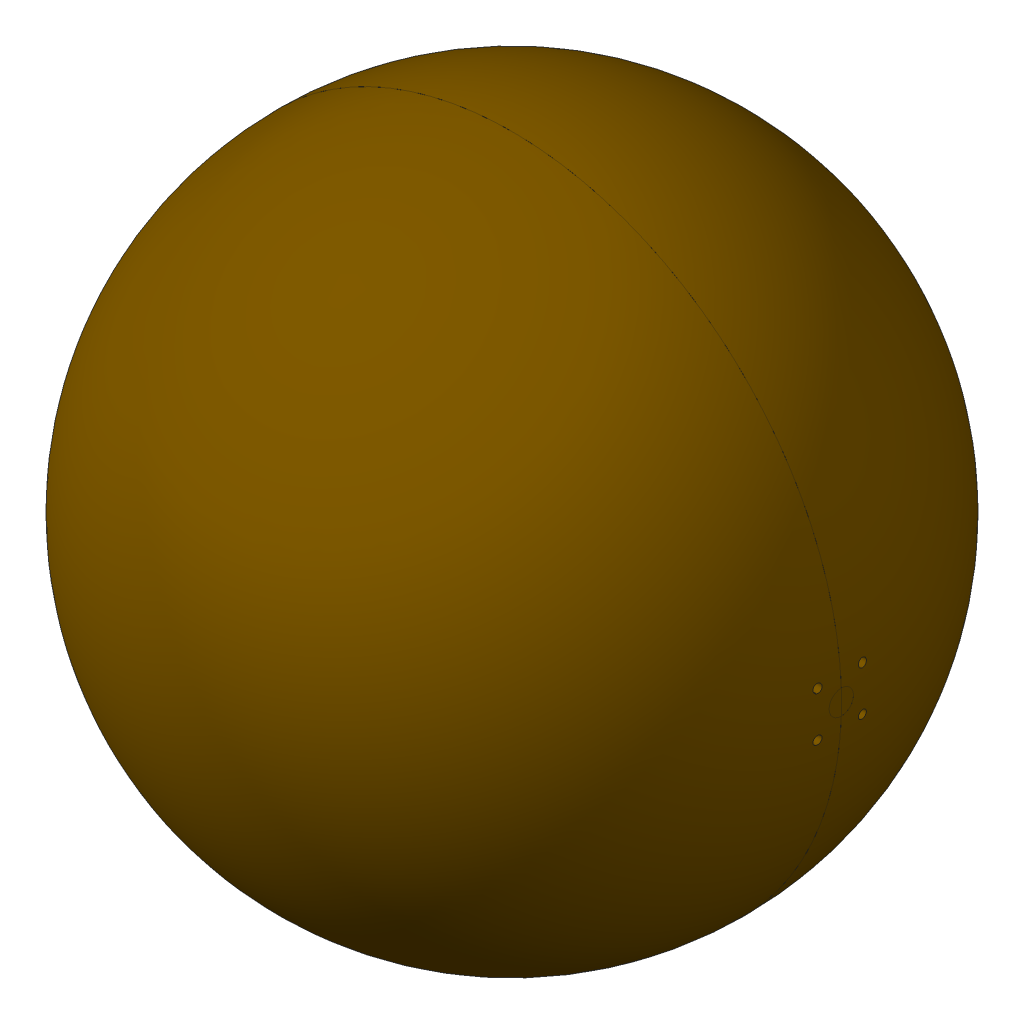
SolidWorks assembly Assembly_robot, configuration По умолчанию. Lengths in mm.
Overall size (270 270 270).
84 component instances, 36 part files, 189 mates.
Components (placement in the parent):
- Body middle part p2_1-1: Body middle part p2_1 [только доя мотора] at (-55.75 0 0) size (72.16 54.84 23.14)
- Body middle part p1-1: Body middle part p1 [только доя мотора] at (-55.6 0 0) size (19.6 42.93 42.93)
- Body middle part p3_1-1: Body middle part p3_1 [только доя мотора] at (-55.9 0 0) size (19.84 11.51 10.97)
- Body middle part p3_2-1: Body middle part p3_2 [только доя мотора] at (-55.9 0 -33.729) size (19.6 9.2 9.2)
- Body middle part p2_2-1: Body middle part p2_2 [только доя мотора] at (-55.75 0 0) size (72 54.84 18.08)
- Body right part-1: Body right part [для аккумулятора] at (114.6 0 0) x (-1 0 0) z (0 -1 0) size (59 42.93 54.93)
- Body left part-1: Body left part [для аккумулятора] at (-114.6 0 0) size (59 42.93 42.93)
- Shaft 4х280mm-1: Shaft 4х280mm [По умолчанию] at (117.5 16.8645 16.8645) x (0 1 0) z (0 0 1) size (4 235 4)
- Shaft 4х280mm-2: Shaft 4х280mm [По умолчанию] at (117.5 -16.8645 16.8645) x (0 1 0) z (0 0 1) size (4 235 4)
- Shaft 4х280mm-3: Shaft 4х280mm [По умолчанию] at (117.5 16.8645 -16.8645) x (0 1 0) z (0 0 1) size (4 235 4)
- Shaft 4х280mm-4: Shaft 4х280mm [По умолчанию] at (117.5 -16.8645 -16.8645) x (0 1 0) z (0 0 1) size (4 235 4)
- Bearing small-1: Bearing small [По умолчанию] at (112.3 0 0) x (0 1 0) z (0 0 1) size (15 5 15)
- Bearing moumt-1: Bearing moumt [под подшипник] at (112.6 0 0) x (0 0.707107 -0.707107) z (0 0.707107 0.707107) size (36.3 7.8 36.3)
- Bearing small-2: Bearing small [По умолчанию] at (-107.3 0 0) x (0 1 0) z (0 0 1) size (15 5 15)
- Bearing moumt-2: Bearing moumt [под подшипник] at (-112.6 0 0) x (0 -0.707107 -0.707107) z (0 -0.707107 0.707107) size (36.3 7.8 36.3)
- IG320014-1: IG320014 [По умолчанию] at (-68.8 0 0) size (118.3 36 36) (flexible)
  - IG320014 ч2 (мотор)-1: IG320014 ч2 (мотор) [По умолчанию] at origin size (76 36 36)
  - IG320014 ч1 (редуктор)-1: IG320014 ч1 (редуктор) [По умолчанию] at origin size (26 35 35)
  - IG320014 ч3 (вал)-1: IG320014 ч3 (вал) [По умолчанию] at (16.3 0 0) x (0 -0.305233 0.952278) z (0 -0.952278 -0.305233) size (6 16.3 6)
- Screw M3x10-1: Screw M3x10 [По умолчанию] at (-57.8 9.1924 9.1924) x (0 -1 0) z (0 0 1) size (5.7 12.2 5.7)
- Screw M3x10-2: Screw M3x10 [По умолчанию] at (-57.8 9.1924 -9.1924) x (0 -1 0) z (0 0 1) size (5.7 12.2 5.7)
- Screw M3x10-3: Screw M3x10 [По умолчанию] at (-57.8 -9.1924 -9.1924) x (0 -1 0) z (0 0 1) size (5.7 12.2 5.7)
- Screw M3x10-4: Screw M3x10 [По умолчанию] at (-57.8 -9.1924 9.1924) x (0 -1 0) z (0 0 1) size (5.7 12.2 5.7)
- Screw M3x10-5: Screw M3x10 [По умолчанию] at (-116.8 9.1924 -9.1924) x (0 -1 0) z (0 0 1) size (5.7 12.2 5.7)
- Screw M3x10-6: Screw M3x10 [По умолчанию] at (-116.8 9.1924 9.1924) x (0 -1 0) z (0 0 1) size (5.7 12.2 5.7)
- Screw M3x10-7: Screw M3x10 [По умолчанию] at (-116.8 -9.1924 -9.1924) x (0 -1 0) z (0 0 1) size (5.7 12.2 5.7)
- Screw M3x10-8: Screw M3x10 [По умолчанию] at (-116.8 -9.1924 9.1924) x (0 -1 0) z (0 0 1) size (5.7 12.2 5.7)
- Screw M3x10-9: Screw M3x10 [По умолчанию] at (116.8 9.1924 -9.1924) x (0 1 0) z (0 0 1) size (5.7 12.2 5.7)
- Screw M3x10-10: Screw M3x10 [По умолчанию] at (116.8 -9.1924 -9.1924) x (0 1 0) z (0 0 1) size (5.7 12.2 5.7)
- Screw M3x10-11: Screw M3x10 [По умолчанию] at (116.8 9.1924 9.1924) x (0 1 0) z (0 0 1) size (5.7 12.2 5.7)
- Screw M3x10-12: Screw M3x10 [По умолчанию] at (116.8 -9.1924 9.1924) x (0 1 0) z (0 0 1) size (5.7 12.2 5.7)
- Coupling-1: Coupling [По умолчанию] at (-58.8 0 0) x (0 0.305233 -0.952278) z (0 0.952278 0.305233) size (18 25 20.23)
- Shaft 6х60mm-1: Shaft 6х60mm [По умолчанию] at (-69.8 0 0) x (0 -0.305233 0.952278) z (0 -0.952278 -0.305233) size (6 60 5.3)
- Screw M3x10-14: Screw M3x10 [По умолчанию] at (-78.8 12.7891 4.0993) x (-0.440876 -0.273967 0.854734) z (0.897568 -0.13457 0.419836) size (5.7 12.2 5.7)
- Screw M3x10-15: Screw M3x10 [По умолчанию] at (-63.8 12.7891 4.0993) x (0.719714 -0.211914 0.661138) z (0.69427 0.21968 -0.685368) size (5.7 12.2 5.7)
- Servo mount v2-1: Servo mount v2 [По умолчанию] at (-13 -0.0035 -0.1355) x (0 0 -1) z (0 -1 0) size (31.72 46 59.48)
- MG995_Servo-1: MG995_Servo [Default] at (65.9061 61.1075 44.196) x (0 1 0) z (-1 0 0) size (60.1 47.6 22.25) (flexible)
  - TowerPro-MG995-1: TowerPro-MG995 [Default] at (-71.4122 -13.9185 65.9061) size (60.1 40.2 19.8)
  - TowerPro-MG995_pulley-1: TowerPro-MG995_pulley [Default] at (-61.1622 -19.0185 65.9061) x (0.189958 0 0.981792) z (0.981792 0 -0.189958) size (5.79 14.9 5.78)
  - TowerPro-MG995_arm-1: TowerPro-MG995_arm [По умолчанию] at (-61.1622 -25.0185 65.9061) x (0.996011 0 -0.089235) z (0.089235 0 0.996011) size (20.5 5.3 20.5)
- Screw M4x10-1: Screw M4x10 [По умолчанию] at (5 13.9453 54.1145) x (0.157718 0.987484 0) z (-0.987484 0.157718 0) size (8 12.2 8)
- Screw M4x10-2: Screw M4x10 [По умолчанию] at (-5 13.9453 54.1145) x (0.038416 0.999262 0) z (-0.999262 0.038416 0) size (8 12.2 8)
- Screw M4x10-3: Screw M4x10 [По умолчанию] at (5 -34.5547 54.1145) x (0.758042 -0.652206 0) z (0.652206 0.758042 0) size (8 12.2 8)
- Screw M4x10-4: Screw M4x10 [По умолчанию] at (-5 -34.5547 54.1145) x (0.226836 0.973933 0) z (-0.973933 0.226836 0) size (8 12.2 8)
- Screw M3x10-16: Screw M3x10 [По умолчанию] at (-18 7.8153 39.2145) x (1 0 0) z (0 1 0) size (5.7 12.2 5.7)
- Screw M3x10-17: Screw M3x10 [По умолчанию] at (-18 -24.0547 39.2145) x (0.735572 -0.677446 0) z (0.677446 0.735572 0) size (5.7 12.2 5.7)
- Screw M3x10-18: Screw M3x10 [По умолчанию] at (18 7.8153 39.2145) x (-0.896782 0.442473 0) z (-0.442473 -0.896782 0) size (5.7 12.2 5.7)
- Screw M3x10-19: Screw M3x10 [По умолчанию] at (18 -24.0547 39.2145) x (0.107392 -0.994217 0) z (0.994217 0.107392 0) size (5.7 12.2 5.7)
- Screw M6x12-1: Screw M6x12 [По умолчанию] at (0 -0.0524 -36.2129) x (0.808509 -0.588484 0) z (-0.588484 -0.808509 0) size (10 16 10)
- Bearing small-3: Bearing small [По умолчанию] at (0 -0.0524 -32.2129) x (-0.489561 0.871969 0) z (0.871969 0.489561 0) size (15 5 15)
- Spacer-1: Spacer [По умолчанию] at (0 -0.0524 -27.2129) x (1 0 0) z (0 -1 0) size (11.8 1.5 11.8)
- Nut M3-1: Nut M3 [По умолчанию] at (18 7.8153 20.1645) x (0.5 0.866025 0) z (0.866025 -0.5 0) size (6 2.3 5.2)
- Nut M3-2: Nut M3 [По умолчанию] at (-18 7.8153 20.1645) x (0.5 0.866025 0) z (0.866025 -0.5 0) size (6 2.3 5.2)
- Nut M3-3: Nut M3 [По умолчанию] at (18 -24.0486 18.8529) x (0.5 0.866025 0) z (0.866025 -0.5 0) size (6 2.3 5.2)
- Nut M3-4: Nut M3 [По умолчанию] at (62.45 29.2845 14.9645) x (1 0 0) z (0 -1 0) size (6 2.3 5.2)
- Nut M3-5: Nut M3 [По умолчанию] at (-18 -24.0486 18.8529) x (0.5 0.866025 0) z (0.866025 -0.5 0) size (6 2.3 5.2)
- Nut M3-6: Nut M3 [По умолчанию] at (98.95 29.2845 14.9645) x (1 0 0) z (0 -1 0) size (6 2.3 5.2)
- Nut M3-7: Nut M3 [По умолчанию] at (62.45 -7.2155 14.9645) x (1 0 0) z (0 -1 0) size (6 2.3 5.2)
- Nut M3-8: Nut M3 [По умолчанию] at (98.95 -7.2155 14.9645) x (1 0 0) z (0 -1 0) size (6 2.3 5.2)
- Nut M4-1: Nut M4 [По умолчанию] at (-114.6 16.8645 -16.8645) x (0 1 0) z (0 0 1) size (7.85 3 6.8)
- Nut M4-2: Nut M4 [По умолчанию] at (-114.6 -16.8645 -16.8645) x (0 1 0) z (0 0 1) size (7.85 3 6.8)
- Nut M4-3: Nut M4 [По умолчанию] at (-114.6 -16.8645 16.8645) x (0 1 0) z (0 0 1) size (7.85 3 6.8)
- Nut M4-4: Nut M4 [По умолчанию] at (-114.6 16.8645 16.8645) x (0 1 0) z (0 0 1) size (7.85 3 6.8)
- Nut M4-5: Nut M4 [По умолчанию] at (117.6 16.8645 -16.8645) x (0 1 0) z (0 0 1) size (7.85 3 6.8)
- Nut M4-6: Nut M4 [По умолчанию] at (117.6 16.8645 16.8645) x (0 1 0) z (0 0 1) size (7.85 3 6.8)
- Nut M4-7: Nut M4 [По умолчанию] at (117.6 -16.8645 16.8645) x (0 1 0) z (0 0 1) size (7.85 3 6.8)
- Nut M4-8: Nut M4 [По умолчанию] at (117.6 -16.8645 -16.8645) x (0 1 0) z (0 0 1) size (7.85 3 6.8)
- Body battery p1-1: Body battery p1 [По умолчанию] at (-39.5 -40.8461 0) x (0 -1 0) z (0 0 1) size (38.3 19.8 40)
- Body battery p2-1: Body battery p2 [По умолчанию] at (-39.5 -40.8461 0) x (0 -1 0) z (0 0 1) size (38.3 18 40)
- new battery (tattu 11.1V 1550mAh)-1: new battery (tattu 11.1V 1550mAh) [По умолчанию] at (-37.3 -39.8461 0) x (0 1 0) z (0 0 -1) size (43.54 93.43 27)
- Screw M3x6-1: Screw M3x6 [По умолчанию] at (-29.5 -27.6961 -20.6129) x (1 0 0) z (0 -1 0) size (5.7 8.2 5.7)
- Screw M3x6-2: Screw M3x6 [По умолчанию] at (29.5 -27.6961 -20.6129) x (1 0 0) z (0 -1 0) size (5.7 8.2 5.7)
- Screw M3x6-3: Screw M3x6 [По умолчанию] at (-29.5 -27.6961 20.6129) x (1 0 0) z (0 1 0) size (5.7 8.2 5.7)
- Screw M3x6-4: Screw M3x6 [По умолчанию] at (29.5 -27.6961 20.6129) x (1 0 0) z (0 1 0) size (5.7 8.2 5.7)
- Shaft 6х30mm-1: Shaft 6х30mm [По умолчанию] at (129.8 0 0) x (0 -0.163235 0.986587) z (0 -0.986587 -0.163235) size (6 30 5.3)
- Case mount-1: Case mount [По умолчанию] at (129.8 0 0) x (0 -0.163235 0.986587) z (0 -0.986587 -0.163235) size (35 11 31.69)
- Case mount-2: Case mount [По умолчанию] at (-129.8 0 0) x (0 0.305233 -0.952278) z (0 -0.952278 -0.305233) size (35 11 31.69)
- Sinker-1: Sinker [По умолчанию] at (-0.2619 -121.0544 20.8871) x (0 0 -1) z (0.999998 -0.002164 0) size (71 47 36)
- Sinker mount bearing-1: Sinker mount bearing [По умолчанию] at (-0.0343 -15.9045 -32.2129) x (0.999998 -0.002164 0) z (-0.002164 -0.999998 0) size (25 5 50)
- Sinker mount servo-2: Sinker mount servo [По умолчанию] at (-0.0343 -15.9069 69.2145) x (0.999998 -0.002164 0) z (-0.002164 -0.999998 0) size (25 4 50)
- Sinker mount-2: Sinker mount [По умолчанию] at (-0.0977 -45.2024 68.9871) x (0.999998 -0.002164 0) z (0.002164 0.999998 0) size (25 12.6 70)
- Sinker mount-3: Sinker mount [По умолчанию] at (-0.0977 -45.2024 -27.2129) x (-0.999998 0.002164 0) z (0.002164 0.999998 0) size (25 12.6 70)
- Case half-1: Case half [По умолчанию] at origin size (270 270 135)
- Case half-2: Case half [По умолчанию] x (-1 0 0) z (0 0 -1) size (270 270 135)
Mates (geometry in assembly coordinates):
- Совпадение1: coincident: point of ?
- Совпадение2: coincident aligned: plane of Body middle part p2_1-1 through (-55.75 0 0) normal (0 0 1); plane of assembly through (0 0 0) normal (0 0 1)
- Параллельность1: parallel aligned: plane of Body middle part p2_1-1 through (-55.75 0 0) normal (1 0 0); plane of assembly through (0 0 0) normal (1 0 0)
- Концентричный1: concentric anti-aligned: cylinder of Body middle part p2_1-1 through (68.7608 16.8645 16.8645) axis (-1 0 0) radius 2.1; cylinder of Shaft 4х280mm-1 through (-117.5 16.8645 16.8645) axis (1 0 0) radius 2
- Ширина1: width anti-aligned: plane of Body middle part p2_1-1 through (-36 -19.3785 -16.1529) normal (-1 0 0); plane of Body middle part p2_1-1 through (36 0 0) normal (1 0 0); plane of Shaft 4х280mm-1 through (117.5 16.8645 16.8645) normal (1 0 0); plane of Shaft 4х280mm-1 through (-117.5 16.8645 16.8645) normal (-1 0 0)
- Концентричный2: concentric anti-aligned: cylinder of Body middle part p2_1-1 through (68.7608 -16.8645 16.8645) axis (-1 0 0) radius 2.1; cylinder of Shaft 4х280mm-2 through (-117.5 -16.8645 16.8645) axis (1 0 0) radius 2
- Совпадение4: coincident aligned: plane of Shaft 4х280mm-1 through (-117.5 16.8645 16.8645) normal (-1 0 0); plane of Shaft 4х280mm-2 through (-117.5 -16.8645 16.8645) normal (-1 0 0)
- Концентричный3: concentric anti-aligned: cylinder of Body middle part p1-1 through (-54.1 0 0) axis (1 0 0) radius 18.25; cylinder of IG320014-1/IG320014 ч1 (редуктор)-1 through (-68.8 0 0) axis (-1 0 0) radius 17.5
- Совпадение5: coincident anti-aligned: plane of Body middle part p1-1 through (-49.5 0 0) normal (1 0 0); plane of IG320014-1/IG320014 ч1 (редуктор)-1 through (-49.5 0 0) normal (-1 0 0)
- Концентричный4: concentric aligned: cylinder of Body middle part p1-1 through (55.9 9.1924 9.1924) axis (-1 0 0) radius 1.5; cylinder of IG320014-1/IG320014 ч1 (редуктор)-1 through (-42.5 9.1924 9.1924) axis (-1 0 0) radius 1.5
- Концентричный9: concentric aligned: cylinder of Body middle part p1-1 through (55.9 9.1924 -9.1924) axis (-1 0 0) radius 1.5; cylinder of Screw M3x10-2 through (-45.6 9.1924 -9.1924) axis (-1 0 0) radius 1.4
- Концентричный10: concentric aligned: cylinder of Body middle part p1-1 through (55.9 9.1924 9.1924) axis (-1 0 0) radius 1.5; cylinder of Screw M3x10-1 through (-45.6 9.1924 9.1924) axis (-1 0 0) radius 1.4
- Концентричный11: concentric aligned: cylinder of Body middle part p1-1 through (55.9 -9.1924 -9.1924) axis (-1 0 0) radius 1.5; cylinder of Screw M3x10-3 through (-45.6 -9.1924 -9.1924) axis (-1 0 0) radius 1.4
- Концентричный12: concentric aligned: cylinder of Body middle part p1-1 through (55.9 -9.1924 9.1924) axis (-1 0 0) radius 1.5; cylinder of Screw M3x10-4 through (-45.6 -9.1924 9.1924) axis (-1 0 0) radius 1.4
- Совпадение8: coincident anti-aligned: plane of Body middle part p1-1 through (-55.6 0 0) normal (-1 0 0); plane of Screw M3x10-2 through (-55.6 9.1924 -9.1924) normal (1 0 0)
- Совпадение9: coincident anti-aligned: plane of Body middle part p1-1 through (-55.6 0 0) normal (-1 0 0); plane of Screw M3x10-1 through (-55.6 9.1924 9.1924) normal (1 0 0)
- Совпадение10: coincident anti-aligned: plane of Body middle part p1-1 through (-55.6 0 0) normal (-1 0 0); plane of Screw M3x10-3 through (-55.6 -9.1924 -9.1924) normal (1 0 0)
- Совпадение11: coincident anti-aligned: plane of Body middle part p1-1 through (-55.6 0 0) normal (-1 0 0); plane of Screw M3x10-4 through (-55.6 -9.1924 9.1924) normal (1 0 0)
- Концентричный13: concentric anti-aligned: cylinder of Body middle part p1-1 through (68.9108 16.8645 16.8645) axis (-1 0 0) radius 2.1; cylinder of Shaft 4х280mm-1 through (-117.5 16.8645 16.8645) axis (1 0 0) radius 2
- Концентричный14: concentric anti-aligned: cylinder of Body middle part p1-1 through (68.9108 -16.8645 16.8645) axis (-1 0 0) radius 2.1; cylinder of Shaft 4х280mm-2 through (-117.5 -16.8645 16.8645) axis (1 0 0) radius 2
- Совпадение12: coincident anti-aligned: plane of Body middle part p2_1-1 through (-36 -19.3785 16.1529) normal (-1 0 0); plane of Body middle part p1-1 through (-36 0 0) normal (1 0 0)
- Концентричный15: concentric anti-aligned: cylinder of Body middle part p1-1 through (68.9108 16.8645 -16.8645) axis (-1 0 0) radius 2.1; cylinder of Shaft 4х280mm-3 through (-117.5 16.8645 -16.8645) axis (1 0 0) radius 2
- Совпадение13: coincident aligned: plane of Shaft 4х280mm-1 through (-117.5 16.8645 16.8645) normal (-1 0 0); plane of Shaft 4х280mm-3 through (-117.5 16.8645 -16.8645) normal (-1 0 0)
- Концентричный16: concentric anti-aligned: cylinder of Body middle part p1-1 through (68.9108 -16.8645 -16.8645) axis (-1 0 0) radius 2.1; cylinder of Shaft 4х280mm-4 through (-117.5 -16.8645 -16.8645) axis (1 0 0) radius 2
- Совпадение14: coincident aligned: plane of Shaft 4х280mm-3 through (-117.5 16.8645 -16.8645) normal (-1 0 0); plane of Shaft 4х280mm-4 through (-117.5 -16.8645 -16.8645) normal (-1 0 0)
- Концентричный17: concentric anti-aligned: cylinder of Body middle part p2_2-1 through (68.7608 -16.8645 -16.8645) axis (-1 0 0) radius 2.1; cylinder of Shaft 4х280mm-4 through (-117.5 -16.8645 -16.8645) axis (1 0 0) radius 2
- Концентричный18: concentric anti-aligned: cylinder of Body middle part p2_2-1 through (68.7608 16.8645 -16.8645) axis (-1 0 0) radius 2.1; cylinder of Shaft 4х280mm-3 through (-117.5 16.8645 -16.8645) axis (1 0 0) radius 2
- Совпадение15: coincident anti-aligned: plane of Body middle part p1-1 through (-36 0 0) normal (1 0 0); plane of Body middle part p2_2-1 through (-36 -19.3785 -16.1529) normal (-1 0 0)
- Концентричный20: concentric anti-aligned: cylinder of Body middle part p3_2-1 through (68.6108 16.8645 -16.8645) axis (-1 0 0) radius 2.1; cylinder of Shaft 4х280mm-3 through (-117.5 16.8645 -16.8645) axis (1 0 0) radius 2
- Совпадение16: coincident anti-aligned: plane of Body middle part p3_2-1 through (36 0 -33.729) normal (-1 0 0); plane of Body middle part p2_2-1 through (36 0 0) normal (1 0 0)
- Концентричный21: concentric anti-aligned: cylinder of Body middle part p3_1-1 through (68.6108 -16.8645 16.8645) axis (-1 0 0) radius 2.1; cylinder of Shaft 4х280mm-2 through (-117.5 -16.8645 16.8645) axis (1 0 0) radius 2
- Совпадение17: coincident anti-aligned: plane of Body middle part p2_1-1 through (36 -19.3785 16.1529) normal (1 0 0); plane of Body middle part p3_1-1 through (36 0 0) normal (-1 0 0)
- Концентричный22: concentric anti-aligned: cylinder of Bearing small-2 through (-112.3 0 0) axis (1 0 0) radius 7.5; cylinder of Bearing moumt-2 through (-107.3 0 0) axis (-1 0 0) radius 7.6
- Совпадение18: coincident anti-aligned: plane of Bearing small-2 through (-107.3 0 0) normal (1 0 0); plane of Bearing moumt-2 through (-107.3 0 0) normal (-1 0 0)
- Совпадение19: coincident anti-aligned: plane of Body left part-1 through (-112.6 0 0) normal (1 0 0); plane of Bearing moumt-2 through (-112.6 0 0) normal (-1 0 0)
- Концентричный23: concentric aligned: cylinder of Body left part-1 through (-55.6 0 0) axis (-1 0 0) radius 18.25; cylinder of Bearing moumt-2 through (-107.3 0 0) axis (-1 0 0) radius 18.15
- Концентричный24: concentric anti-aligned: cylinder of Body left part-1 through (-42.5892 16.8645 16.8645) axis (-1 0 0) radius 2.1; cylinder of Shaft 4х280mm-1 through (-117.5 16.8645 16.8645) axis (1 0 0) radius 2
- Концентричный25: concentric anti-aligned: cylinder of Body left part-1 through (-42.5892 -16.8645 16.8645) axis (-1 0 0) radius 2.1; cylinder of Shaft 4х280mm-2 through (-117.5 -16.8645 16.8645) axis (1 0 0) radius 2
- Концентричный26: concentric anti-aligned: cylinder of Body left part-1 through (-55.6 9.1924 9.1924) axis (-1 0 0) radius 1.5; cylinder of Bearing moumt-2 through (-112.6 9.1924 9.1924) axis (1 0 0) radius 1.3
- Концентричный27: concentric aligned: cylinder of Body left part-1 through (-55.6 9.1924 -9.1924) axis (-1 0 0) radius 1.5; cylinder of Screw M3x10-5 through (-104.6 9.1924 -9.1924) axis (-1 0 0) radius 1.4
- Концентричный28: concentric aligned: cylinder of Body left part-1 through (-55.6 9.1924 9.1924) axis (-1 0 0) radius 1.5; cylinder of Screw M3x10-6 through (-104.6 9.1924 9.1924) axis (-1 0 0) radius 1.4
- Концентричный29: concentric aligned: cylinder of Body left part-1 through (-55.6 -9.1924 -9.1924) axis (-1 0 0) radius 1.5; cylinder of Screw M3x10-7 through (-104.6 -9.1924 -9.1924) axis (-1 0 0) radius 1.4
- Концентричный30: concentric aligned: cylinder of Body left part-1 through (-55.6 -9.1924 9.1924) axis (-1 0 0) radius 1.5; cylinder of Screw M3x10-8 through (-104.6 -9.1924 9.1924) axis (-1 0 0) radius 1.4
- Совпадение20: coincident anti-aligned: plane of Body left part-1 through (-114.6 0 0) normal (-1 0 0); plane of Screw M3x10-6 through (-114.6 9.1924 9.1924) normal (1 0 0)
- Совпадение21: coincident anti-aligned: plane of Body left part-1 through (-114.6 0 0) normal (-1 0 0); plane of Screw M3x10-5 through (-114.6 9.1924 -9.1924) normal (1 0 0)
- Совпадение22: coincident anti-aligned: plane of Body left part-1 through (-114.6 0 0) normal (-1 0 0); plane of Screw M3x10-7 through (-114.6 -9.1924 -9.1924) normal (1 0 0)
- Совпадение23: coincident anti-aligned: plane of Body left part-1 through (-114.6 0 0) normal (-1 0 0); plane of Screw M3x10-8 through (-114.6 -9.1924 9.1924) normal (1 0 0)
- Концентричный31: concentric aligned: cylinder of Bearing small-1 through (107.3 0 0) axis (1 0 0) radius 7.5; cylinder of Bearing moumt-1 through (107.3 0 0) axis (1 0 0) radius 7.6
- Совпадение24: coincident anti-aligned: plane of Bearing small-1 through (107.3 0 0) normal (-1 0 0); plane of Bearing moumt-1 through (107.3 0 0) normal (1 0 0)
- Совпадение25: coincident anti-aligned: plane of Body right part-1 through (112.6 0 0) normal (-1 0 0); plane of Bearing moumt-1 through (112.6 0 0) normal (1 0 0)
- Концентричный32: concentric aligned: cylinder of Body right part-1 through (42.5892 16.8645 16.8645) axis (1 0 0) radius 2.1; cylinder of Shaft 4х280mm-1 through (-117.5 16.8645 16.8645) axis (1 0 0) radius 2
- Концентричный33: concentric aligned: cylinder of Body right part-1 through (42.5892 -16.8645 16.8645) axis (1 0 0) radius 2.1; cylinder of Shaft 4х280mm-2 through (-117.5 -16.8645 16.8645) axis (1 0 0) radius 2
- Концентричный34: concentric aligned: cylinder of Body right part-1 through (55.6 0 0) axis (1 0 0) radius 18.25; cylinder of Bearing moumt-1 through (107.3 0 0) axis (1 0 0) radius 18.15
- Концентричный35: concentric anti-aligned: cylinder of Body right part-1 through (55.6 9.1924 -9.1924) axis (1 0 0) radius 1.5; cylinder of Bearing moumt-1 through (112.6 9.1924 -9.1924) axis (-1 0 0) radius 1.3
- Концентричный36: concentric aligned: cylinder of Body right part-1 through (55.6 9.1924 -9.1924) axis (1 0 0) radius 1.5; cylinder of Screw M3x10-9 through (104.6 9.1924 -9.1924) axis (1 0 0) radius 1.4
- Концентричный37: concentric aligned: cylinder of Body right part-1 through (55.6 -9.1924 -9.1924) axis (1 0 0) radius 1.5; cylinder of Screw M3x10-10 through (104.6 -9.1924 -9.1924) axis (1 0 0) radius 1.4
- Концентричный38: concentric aligned: cylinder of Body right part-1 through (55.6 9.1924 9.1924) axis (1 0 0) radius 1.5; cylinder of Screw M3x10-11 through (104.6 9.1924 9.1924) axis (1 0 0) radius 1.4
- Концентричный39: concentric aligned: cylinder of Body right part-1 through (55.6 -9.1924 9.1924) axis (1 0 0) radius 1.5; cylinder of Screw M3x10-12 through (104.6 -9.1924 9.1924) axis (1 0 0) radius 1.4
- Совпадение26: coincident anti-aligned: plane of Body right part-1 through (114.6 0 0) normal (1 0 0); plane of Screw M3x10-11 through (114.6 9.1924 9.1924) normal (-1 0 0)
- Совпадение27: coincident anti-aligned: plane of Body right part-1 through (114.6 0 0) normal (1 0 0); plane of Screw M3x10-10 through (114.6 -9.1924 -9.1924) normal (-1 0 0)
- Совпадение28: coincident anti-aligned: plane of Body right part-1 through (114.6 0 0) normal (1 0 0); plane of Screw M3x10-9 through (114.6 9.1924 -9.1924) normal (-1 0 0)
- Совпадение29: coincident anti-aligned: plane of Body right part-1 through (114.6 0 0) normal (1 0 0); plane of Screw M3x10-12 through (114.6 -9.1924 9.1924) normal (-1 0 0)
- Совпадение30: coincident anti-aligned: plane of Body middle part p3_1-1 through (55.6 0 0) normal (1 0 0); plane of Body right part-1 through (55.6 0 0) normal (-1 0 0)
- Концентричный40: concentric aligned: cylinder of IG320014-1/IG320014 ч3 (вал)-1 through (-68.8 0 0) axis (1 0 0) radius 3; cylinder of Coupling-1 through (-83.8 0 0) axis (1 0 0) radius 3.05
- Параллельность2: parallel anti-aligned: plane of IG320014-1/IG320014 ч3 (вал)-1 through (-56.8 2.8869 -0.8161) normal (0 0.952278 0.305233); plane of Coupling-1 through (-70.8 1.8888 3.0512) normal (0 -0.952278 -0.305233)
- Расстояние2: distance = 10 mm anti-aligned: plane of IG320014-1/IG320014 ч3 (вал)-1 through (-68.8 0 0) normal (-1 0 0); plane of Coupling-1 through (-58.8 0 0) normal (1 0 0)
- Концентричный41: concentric aligned: cylinder of Coupling-1 through (-83.8 0 0) axis (1 0 0) radius 3.05; cylinder of Shaft 6х60mm-1 through (-129.8 0 0) axis (1 0 0) radius 3
- Параллельность3: parallel anti-aligned: plane of Coupling-1 through (-70.8 1.8888 3.0512) normal (0 -0.952278 -0.305233); plane of Shaft 6х60mm-1 through (-69.8 2.9533 -1.6787) normal (0 0.952278 0.305233)
- Расстояние3: distance = 14 mm anti-aligned: plane of Coupling-1 through (-83.8 0 0) normal (-1 0 0); plane of Shaft 6х60mm-1 through (-69.8 0 0) normal (1 0 0)
- Концентричный42: concentric aligned: cylinder of Coupling-1 through (-63.8 -0.7333 -0.235) axis (0 0.952278 0.305233) radius 1.5; cylinder of Screw M3x10-15 through (-63.8 1.1713 0.3754) axis (0 0.952278 0.305233) radius 1.4
- Концентричный43: concentric aligned: cylinder of Coupling-1 through (-78.8 -0.7333 -0.235) axis (0 0.952278 0.305233) radius 1.5; cylinder of Screw M3x10-14 through (-78.8 1.1713 0.3754) axis (0 0.952278 0.305233) radius 1.4
- Совпадение36: coincident anti-aligned: plane of Coupling-1 through (-58.8 10.6941 3.4278) normal (0 0.952278 0.305233); plane of Screw M3x10-15 through (-63.8 10.6941 3.4278) normal (0 -0.952278 -0.305233)
- Совпадение37: coincident anti-aligned: plane of Coupling-1 through (-58.8 10.6941 3.4278) normal (0 0.952278 0.305233); plane of Screw M3x10-14 through (-78.8 10.6941 3.4278) normal (0 -0.952278 -0.305233)
- Совпадение38: coincident anti-aligned: plane of Body middle part p1-1 through (-55.6 0 0) normal (-1 0 0); plane of Body left part-1 through (-55.6 0 0) normal (1 0 0)
- Совпадение40: coincident anti-aligned: plane of Body middle part p2_1-1 through (-55.75 0 31.4645) normal (0 0 1); plane of Servo mount v2-1 through (-13 -0.0035 31.4645) normal (0 0 -1)
- Концентричный44: concentric aligned: cylinder of Body middle part p2_1-1 through (-18 7.8153 11.4645) axis (0 0 1) radius 1.5; cylinder of Servo mount v2-1 through (-18 7.8153 17.5443) axis (0 0 1) radius 1.5
- Параллельность4: parallel aligned: cylinder of Body middle part p2_1-1 through (-18 -24.0486 11.4645) axis (0 0 1) radius 1.5; cylinder of Servo mount v2-1 through (-18 -24.0547 17.5443) axis (0 0 1) radius 1.5
- Совпадение41: coincident anti-aligned: plane of Servo mount v2-1 through (11 -38.0447 49.4145) normal (0 0 1); plane of MG995_Servo-1/TowerPro-MG995-1 through (0 -10.3047 49.4145) normal (0 0 -1)
- Ширина2: width anti-aligned: plane of Servo mount v2-1 through (10.15 10.2953 17.6953) normal (-1 0 0); plane of Servo mount v2-1 through (-10.15 10.2953 17.6953) normal (1 0 0); plane of MG995_Servo-1/TowerPro-MG995-1 through (9.9 9.9453 21.6145) normal (1 0 0); plane of MG995_Servo-1/TowerPro-MG995-1 through (-9.9 9.9453 21.6145) normal (-1 0 0)
- Ширина3: width anti-aligned: plane of Servo mount v2-1 through (10.15 -30.9047 17.6953) normal (0 1 0); plane of Servo mount v2-1 through (10.15 10.2953 17.6953) normal (0 -1 0); plane of MG995_Servo-1/TowerPro-MG995-1 through (-9.9 -30.5547 21.6145) normal (0 -1 0); plane of MG995_Servo-1/TowerPro-MG995-1 through (-9.9 9.9453 21.6145) normal (0 1 0)
- Совпадение42: coincident aligned: plane of Body middle part p2_1-1 through (-23 -19.0486 2.0108) normal (-1 0 0); plane of Servo mount v2-1 through (-23 -19.0547 31.4645) normal (-1 0 0)
- Концентричный48: concentric aligned: cylinder of Servo mount v2-1 through (5 13.9453 37.0145) axis (0 0 1) radius 1.85; cylinder of Screw M4x10-1 through (5 13.9453 41.9145) axis (0 0 1) radius 1.85
- Концентричный49: concentric aligned: cylinder of Servo mount v2-1 through (-5 13.9453 37.0145) axis (0 0 1) radius 1.85; cylinder of Screw M4x10-2 through (-5 13.9453 41.9145) axis (0 0 1) radius 1.85
- Концентричный50: concentric aligned: cylinder of Servo mount v2-1 through (5 -34.5547 37.0145) axis (0 0 1) radius 1.85; cylinder of Screw M4x10-3 through (5 -34.5547 41.9145) axis (0 0 1) radius 1.85
- Концентричный51: concentric aligned: cylinder of Servo mount v2-1 through (-5 -34.5547 37.0145) axis (0 0 1) radius 1.85; cylinder of Screw M4x10-4 through (-5 -34.5547 41.9145) axis (0 0 1) radius 1.85
- Совпадение43: coincident anti-aligned: plane of MG995_Servo-1/TowerPro-MG995-1 through (0 -10.3047 51.9145) normal (0 0 1); plane of Screw M4x10-1 through (5 13.9453 51.9145) normal (0 0 -1)
- Совпадение44: coincident anti-aligned: plane of MG995_Servo-1/TowerPro-MG995-1 through (0 -10.3047 51.9145) normal (0 0 1); plane of Screw M4x10-2 through (-5 13.9453 51.9145) normal (0 0 -1)
- Совпадение45: coincident anti-aligned: plane of MG995_Servo-1/TowerPro-MG995-1 through (0 -10.3047 51.9145) normal (0 0 1); plane of Screw M4x10-3 through (5 -34.5547 51.9145) normal (0 0 -1)
- Совпадение46: coincident anti-aligned: plane of MG995_Servo-1/TowerPro-MG995-1 through (0 -10.3047 51.9145) normal (0 0 1); plane of Screw M4x10-4 through (-5 -34.5547 51.9145) normal (0 0 -1)
- Концентричный52: concentric aligned: cylinder of Servo mount v2-1 through (-18 7.8153 17.5443) axis (0 0 1) radius 1.5; cylinder of Screw M3x10-16 through (-18 7.8153 27.0145) axis (0 0 1) radius 1.4
- Концентричный53: concentric aligned: cylinder of Servo mount v2-1 through (-18 -24.0547 17.5443) axis (0 0 1) radius 1.5; cylinder of Screw M3x10-17 through (-18 -24.0547 27.0145) axis (0 0 1) radius 1.4
- Концентричный54: concentric aligned: cylinder of Servo mount v2-1 through (18 7.8153 17.5443) axis (0 0 1) radius 1.5; cylinder of Screw M3x10-18 through (18 7.8153 27.0145) axis (0 0 1) radius 1.4
- Концентричный55: concentric aligned: cylinder of Servo mount v2-1 through (18 -24.0547 17.5443) axis (0 0 1) radius 1.5; cylinder of Screw M3x10-19 through (18 -24.0547 27.0145) axis (0 0 1) radius 1.4
- Совпадение48: coincident anti-aligned: plane of Servo mount v2-1 through (-13 -0.0035 37.0145) normal (0 0 1); plane of Screw M3x10-18 through (18 7.8153 37.0145) normal (0 0 -1)
- Совпадение49: coincident anti-aligned: plane of Servo mount v2-1 through (-13 -0.0035 37.0145) normal (0 0 1); plane of Screw M3x10-19 through (18 -24.0547 37.0145) normal (0 0 -1)
- Совпадение50: coincident anti-aligned: plane of Servo mount v2-1 through (-13 -0.0035 37.0145) normal (0 0 1); plane of Screw M3x10-17 through (-18 -24.0547 37.0145) normal (0 0 -1)
- Совпадение51: coincident anti-aligned: plane of Servo mount v2-1 through (-13 -0.0035 37.0145) normal (0 0 1); plane of Screw M3x10-16 through (-18 7.8153 37.0145) normal (0 0 -1)
- Концентричный58: concentric aligned: cylinder of Body middle part p2_2-1 through (0 -0.0524 -1.4129) axis (0 0 -1) radius 2.5; cylinder of Spacer-1 through (0 -0.0524 -25.7129) axis (0 0 -1) radius 3.15
- Совпадение53: coincident anti-aligned: plane of Body middle part p2_2-1 through (0 -0.0524 -25.7129) normal (0 0 -1); plane of Spacer-1 through (0 -0.0524 -25.7129) normal (0 0 1)
- Концентричный59: concentric aligned: cylinder of Bearing small-3 through (0 -0.0524 -27.2129) axis (0 0 -1) radius 3; cylinder of Spacer-1 through (0 -0.0524 -25.7129) axis (0 0 -1) radius 3.15
- Совпадение54: coincident anti-aligned: plane of Bearing small-3 through (0 -0.0524 -27.2129) normal (0 0 1); plane of Spacer-1 through (0 -0.0524 -27.2129) normal (0 0 -1)
- Концентричный60: concentric aligned: cylinder of Body middle part p2_2-1 through (0 -0.0524 -1.4129) axis (0 0 -1) radius 2.5; cylinder of Screw M6x12-1 through (0 -0.0524 -20.2129) axis (0 0 -1) radius 3
- Совпадение55: coincident anti-aligned: plane of Screw M6x12-1 through (0 -0.0524 -32.2129) normal (0 0 1); plane of Bearing small-3 through (0 -0.0524 -32.2129) normal (0 0 -1)
- Концентричный61: concentric anti-aligned: cylinder of Body middle part p2_1-1 through (18 7.8153 11.4645) axis (0 0 1) radius 1.5; cylinder of Nut M3-1 through (18 7.8153 22.4645) axis (0 0 -1) radius 1.35
- Параллельность5: parallel anti-aligned: plane of Body middle part p2_1-1 through (19.525 10.4567 22.4645) normal (0 -1 0); plane of Nut M3-1 through (19.5 10.4134 22.4645) normal (0 1 0)
- Совпадение57: coincident anti-aligned: plane of Body middle part p2_1-1 through (-55.75 0 22.4645) normal (0 0 -1); plane of Nut M3-1 through (18 7.8153 22.4645) normal (0 0 1)
- Концентричный62: concentric anti-aligned: cylinder of Body middle part p2_1-1 through (18 -24.0486 11.4645) axis (0 0 1) radius 1.5; cylinder of Nut M3-3 through (18 -24.0486 21.1529) axis (0 0 -1) radius 1.35
- Параллельность6: parallel anti-aligned: plane of Body middle part p2_1-1 through (16.475 -21.4072 21.1529) normal (0 -1 0); plane of Nut M3-3 through (19.5 -21.4505 21.1529) normal (0 1 0)
- Совпадение59: coincident anti-aligned: plane of Body middle part p2_1-1 through (-55.75 0 21.1529) normal (0 0 -1); plane of Nut M3-3 through (18 -24.0486 21.1529) normal (0 0 1)
- Концентричный63: concentric anti-aligned: cylinder of Body middle part p2_1-1 through (-18 7.8153 11.4645) axis (0 0 1) radius 1.5; cylinder of Nut M3-2 through (-18 7.8153 22.4645) axis (0 0 -1) radius 1.35
- Параллельность7: parallel anti-aligned: plane of Body middle part p2_1-1 through (-16.475 10.4567 22.4645) normal (0 -1 0); plane of Nut M3-2 through (-16.5 10.4134 22.4645) normal (0 1 0)
- Совпадение61: coincident anti-aligned: plane of Body middle part p2_1-1 through (-55.75 0 22.4645) normal (0 0 -1); plane of Nut M3-2 through (-18 7.8153 22.4645) normal (0 0 1)
- Концентричный64: concentric anti-aligned: cylinder of Body middle part p2_1-1 through (-18 -24.0486 11.4645) axis (0 0 1) radius 1.5; cylinder of Nut M3-5 through (-18 -24.0486 21.1529) axis (0 0 -1) radius 1.35
- Параллельность8: parallel anti-aligned: plane of Body middle part p2_1-1 through (-19.525 -21.4072 21.1529) normal (0 -1 0); plane of Nut M3-5 through (-16.5 -21.4505 21.1529) normal (0 1 0)
- Совпадение63: coincident anti-aligned: plane of Body middle part p2_1-1 through (-55.75 0 21.1529) normal (0 0 -1); plane of Nut M3-5 through (-18 -24.0486 21.1529) normal (0 0 1)
- Концентричный65: concentric anti-aligned: cylinder of Body right part-1 through (62.45 29.2845 -21.4655) axis (0 0 1) radius 1.5; cylinder of Nut M3-4 through (62.45 29.2845 17.2645) axis (0 0 -1) radius 1.35
- Концентричный66: concentric anti-aligned: cylinder of Body right part-1 through (98.95 29.2845 -21.4655) axis (0 0 1) radius 1.5; cylinder of Nut M3-6 through (98.95 29.2845 17.2645) axis (0 0 -1) radius 1.35
- Концентричный67: concentric aligned: cylinder of Body right part-1 through (62.45 -7.2155 21.4655) axis (0 0 -1) radius 1.5; cylinder of Nut M3-7 through (62.45 -7.2155 17.2645) axis (0 0 -1) radius 1.35
- Концентричный68: concentric aligned: cylinder of Body right part-1 through (98.95 -7.2155 21.4655) axis (0 0 -1) radius 1.5; cylinder of Nut M3-8 through (98.95 -7.2155 17.2645) axis (0 0 -1) radius 1.35
- Параллельность9: parallel anti-aligned: plane of Body right part-1 through (100.475 31.9259 14.9645) normal (0 -1 0); plane of Nut M3-6 through (100.45 31.8826 17.2645) normal (0 1 0)
- Параллельность10: parallel anti-aligned: plane of Body right part-1 through (63.975 31.9259 14.9645) normal (0 -1 0); plane of Nut M3-4 through (63.95 31.8826 17.2645) normal (0 1 0)
- Параллельность11: parallel anti-aligned: plane of Body right part-1 through (63.975 -4.5741 14.9645) normal (0 -1 0); plane of Nut M3-7 through (63.95 -4.6174 17.2645) normal (0 1 0)
- Параллельность12: parallel anti-aligned: plane of Body right part-1 through (100.475 -4.5741 14.9645) normal (0 -1 0); plane of Nut M3-8 through (100.45 -4.6174 17.2645) normal (0 1 0)
- Совпадение68: coincident anti-aligned: plane of Body right part-1 through (114.6 0 14.9645) normal (0 0 1); plane of Nut M3-8 through (98.95 -7.2155 14.9645) normal (0 0 -1)
- Совпадение69: coincident anti-aligned: plane of Body right part-1 through (114.6 0 14.9645) normal (0 0 1); plane of Nut M3-7 through (62.45 -7.2155 14.9645) normal (0 0 -1)
- Совпадение70: coincident anti-aligned: plane of Body right part-1 through (114.6 0 14.9645) normal (0 0 1); plane of Nut M3-6 through (98.95 29.2845 14.9645) normal (0 0 -1)
- Совпадение71: coincident anti-aligned: plane of Body right part-1 through (114.6 0 14.9645) normal (0 0 1); plane of Nut M3-4 through (62.45 29.2845 14.9645) normal (0 0 -1)
- Концентричный73: concentric aligned: cylinder of Shaft 4х280mm-3 through (-117.5 16.8645 -16.8645) axis (1 0 0) radius 2; cylinder of Nut M4-1 through (-117.6 16.8645 -16.8645) axis (1 0 0) radius 1.85
- Концентричный74: concentric aligned: cylinder of Shaft 4х280mm-1 through (-117.5 16.8645 16.8645) axis (1 0 0) radius 2; cylinder of Nut M4-4 through (-117.6 16.8645 16.8645) axis (1 0 0) radius 1.85
- Концентричный75: concentric aligned: cylinder of Shaft 4х280mm-4 through (-117.5 -16.8645 -16.8645) axis (1 0 0) radius 2; cylinder of Nut M4-2 through (-117.6 -16.8645 -16.8645) axis (1 0 0) radius 1.85
- Концентричный76: concentric aligned: cylinder of Shaft 4х280mm-2 through (-117.5 -16.8645 16.8645) axis (1 0 0) radius 2; cylinder of Nut M4-3 through (-117.6 -16.8645 16.8645) axis (1 0 0) radius 1.85
- Совпадение76: coincident anti-aligned: plane of Body left part-1 through (-114.6 0 0) normal (-1 0 0); plane of Nut M4-3 through (-114.6 -16.8645 16.8645) normal (1 0 0)
- Совпадение77: coincident anti-aligned: plane of Body left part-1 through (-114.6 0 0) normal (-1 0 0); plane of Nut M4-2 through (-114.6 -16.8645 -16.8645) normal (1 0 0)
- Совпадение78: coincident anti-aligned: plane of Body left part-1 through (-114.6 0 0) normal (-1 0 0); plane of Nut M4-1 through (-114.6 16.8645 -16.8645) normal (1 0 0)
- Совпадение79: coincident anti-aligned: plane of Body left part-1 through (-114.6 0 0) normal (-1 0 0); plane of Nut M4-4 through (-114.6 16.8645 16.8645) normal (1 0 0)
- Концентричный77: concentric aligned: cylinder of Shaft 4х280mm-3 through (-117.5 16.8645 -16.8645) axis (1 0 0) radius 2; cylinder of Nut M4-5 through (114.6 16.8645 -16.8645) axis (1 0 0) radius 1.85
- Концентричный78: concentric aligned: cylinder of Shaft 4х280mm-1 through (-117.5 16.8645 16.8645) axis (1 0 0) radius 2; cylinder of Nut M4-6 through (114.6 16.8645 16.8645) axis (1 0 0) radius 1.85
- Концентричный79: concentric aligned: cylinder of Shaft 4х280mm-4 through (-117.5 -16.8645 -16.8645) axis (1 0 0) radius 2; cylinder of Nut M4-8 through (114.6 -16.8645 -16.8645) axis (1 0 0) radius 1.85
- Концентричный80: concentric aligned: cylinder of Shaft 4х280mm-2 through (-117.5 -16.8645 16.8645) axis (1 0 0) radius 2; cylinder of Nut M4-7 through (114.6 -16.8645 16.8645) axis (1 0 0) radius 1.85
- Совпадение80: coincident anti-aligned: plane of Body right part-1 through (114.6 0 0) normal (1 0 0); plane of Nut M4-5 through (114.6 16.8645 -16.8645) normal (-1 0 0)
- Совпадение81: coincident anti-aligned: plane of Body right part-1 through (114.6 0 0) normal (1 0 0); plane of Nut M4-6 through (114.6 16.8645 16.8645) normal (-1 0 0)
- Совпадение82: coincident anti-aligned: plane of Body right part-1 through (114.6 0 0) normal (1 0 0); plane of Nut M4-7 through (114.6 -16.8645 16.8645) normal (-1 0 0)
- Совпадение83: coincident anti-aligned: plane of Body right part-1 through (114.6 0 0) normal (1 0 0); plane of Nut M4-8 through (114.6 -16.8645 -16.8645) normal (-1 0 0)
- Ширина4: width anti-aligned: plane of Body battery p1-1 through (-37.5 -21.6961 16) normal (0 0 1); plane of Body battery p1-1 through (-37.5 -21.6961 -16) normal (0 0 -1); plane of Body battery p2-1 through (-37.5 -21.6961 -16) normal (0 0 -1); plane of Body battery p2-1 through (-37.5 -21.6961 16) normal (0 0 1)
- Ширина5: width aligned: plane of Body battery p1-1 through (-37.5 -21.6961 16) normal (0 0 1); plane of Body battery p1-1 through (-37.5 -21.6961 -16) normal (0 0 -1); plane of Body middle part p2_1-1 through (-55.75 0 16.1529) normal (0 0 -1); plane of Body middle part p2_2-1 through (-55.75 0 -16.1529) normal (0 0 1)
- Концентричный89: concentric aligned: cylinder of Body middle part p2_1-1 through (-29.5 -27.6961 -21.4645) axis (0 0 1) radius 1.35; cylinder of Body battery p1-1 through (-29.5 -27.6961 -16) axis (0 0 1) radius 1.35
- Концентричный90: concentric aligned: cylinder of Body middle part p2_1-1 through (29.5 -27.6961 -21.4645) axis (0 0 1) radius 1.35; cylinder of Body battery p2-1 through (29.5 -27.6961 -16) axis (0 0 1) radius 1.35
- Параллельность17: parallel anti-aligned: plane of Body battery p1-1 through (-39.5 -40.8461 0) normal (-1 0 0); plane of Body battery p2-1 through (37.5 -40.8461 0) normal (1 0 0)
- Параллельность18: parallel aligned: plane of Servo mount v2-1 through (-13 -40.0447 -0.1355) normal (0 -1 0); plane of Body battery p1-1 through (-37.5 -59.9961 -16) normal (0 -1 0)
- Параллельность19: parallel aligned: plane of Servo mount v2-1 through (-13 -40.0447 -0.1355) normal (0 -1 0); plane of Body battery p2-1 through (-37.5 -59.9961 -16) normal (0 -1 0)
- Ширина6: width anti-aligned: plane of new battery (tattu 11.1V 1550mAh)-1 through (36.7 -57.8461 13.5) normal (0 0 1); plane of new battery (tattu 11.1V 1550mAh)-1 through (36.7 -57.8461 -13.5) normal (0 0 -1); plane of Body battery p1-1 through (37.5 -21.6961 14) normal (0 0 -1); plane of Body battery p1-1 through (37.5 -57.9961 -14) normal (0 0 1)
- Расстояние4: distance = 0.2 mm anti-aligned: plane of new battery (tattu 11.1V 1550mAh)-1 through (-37.3 -39.8461 0) normal (-1 0 0); plane of Body battery p1-1 through (-37.5 -40.8461 0) normal (1 0 0)
- Расстояние5: distance = 0.15 mm anti-aligned: plane of Body battery p2-1 through (37.5 -57.9961 14) normal (0 1 0); plane of new battery (tattu 11.1V 1550mAh)-1 through (36.7 -57.8461 13.5) normal (0 -1 0)
- Концентричный91: concentric aligned: cylinder of Body middle part p2_2-1 through (29.5 -27.6961 21.4645) axis (0 0 -1) radius 1.35; cylinder of Screw M3x6-2 through (29.5 -27.6961 -12.4129) axis (0 0 -1) radius 1.4
- Концентричный92: concentric aligned: cylinder of Body middle part p2_2-1 through (-29.5 -27.6961 21.4645) axis (0 0 -1) radius 1.35; cylinder of Screw M3x6-1 through (-29.5 -27.6961 -12.4129) axis (0 0 -1) radius 1.4
- Совпадение92: coincident anti-aligned: plane of Body middle part p2_2-1 through (-55.75 0 -18.4129) normal (0 0 -1); plane of Screw M3x6-1 through (-29.5 -27.6961 -18.4129) normal (0 0 1)
- Совпадение93: coincident anti-aligned: plane of Body middle part p2_2-1 through (-55.75 0 -18.4129) normal (0 0 -1); plane of Screw M3x6-2 through (29.5 -27.6961 -18.4129) normal (0 0 1)
- Концентричный93: concentric aligned: cylinder of Body middle part p2_1-1 through (-29.5 -27.6961 -21.4645) axis (0 0 1) radius 1.35; cylinder of Screw M3x6-3 through (-29.5 -27.6961 12.4129) axis (0 0 1) radius 1.4
- Концентричный94: concentric aligned: cylinder of Body middle part p2_1-1 through (29.5 -27.6961 -21.4645) axis (0 0 1) radius 1.35; cylinder of Screw M3x6-4 through (29.5 -27.6961 12.4129) axis (0 0 1) radius 1.4
- Совпадение94: coincident anti-aligned: plane of Body middle part p2_1-1 through (-55.75 0 18.4129) normal (0 0 1); plane of Screw M3x6-4 through (29.5 -27.6961 18.4129) normal (0 0 -1)
- Совпадение95: coincident anti-aligned: plane of Body middle part p2_1-1 through (-55.75 0 18.4129) normal (0 0 1); plane of Screw M3x6-3 through (-29.5 -27.6961 18.4129) normal (0 0 -1)
- Концентричный95: concentric aligned: cylinder of Shaft 6х60mm-1 through (-129.8 0 0) axis (1 0 0) radius 3; cylinder of Case mount-2 through (-129.8 0 0) axis (1 0 0) radius 3.1
- Параллельность20: parallel anti-aligned: plane of Shaft 6х60mm-1 through (-69.8 2.9533 -1.6787) normal (0 0.952278 0.305233); plane of Case mount-2 through (-129.8 1.9323 2.4241) normal (0 -0.952278 -0.305233)
- Совпадение97: coincident aligned: plane of Shaft 6х60mm-1 through (-129.8 0 0) normal (-1 0 0); plane of Case mount-2 through (-129.8 0 0) normal (-1 0 0)
- Концентричный96: concentric anti-aligned: cylinder of Shaft 6х30mm-1 through (99.8 0 0) axis (1 0 0) radius 3; cylinder of Case mount-1 through (129.8 0 0) axis (-1 0 0) radius 3.1
- Параллельность21: parallel anti-aligned: plane of Shaft 6х30mm-1 through (129.8 2.6772 -2.091) normal (0 0.986587 0.163235); plane of Case mount-1 through (129.8 2.8259 -1.2744) normal (0 -0.986587 -0.163235)
- Совпадение99: coincident aligned: plane of Shaft 6х30mm-1 through (129.8 0 0) normal (1 0 0); plane of Case mount-1 through (129.8 0 0) normal (1 0 0)
- Концентричный97: concentric aligned: cylinder of Bearing small-1 through (107.3 0 0) axis (1 0 0) radius 3; cylinder of Shaft 6х30mm-1 through (99.8 0 0) axis (1 0 0) radius 3
- Расстояние6: distance = 11.7 mm anti-aligned: plane of Case mount-1 through (126.3 -5.2848 3.7843) normal (-1 0 0); plane of Body right part-1 through (114.6 0 0) normal (1 0 0)
- Концентричный98: concentric aligned: cylinder of Bearing small-3 through (0 -0.0524 -27.2129) axis (0 0 -1) radius 7.5; cylinder of Sinker mount bearing-1 through (0 -0.0524 -27.2129) axis (0 0 -1) radius 7.65
- Совпадение100: coincident aligned: plane of Bearing small-3 through (0 -0.0524 -27.2129) normal (0 0 1); plane of Sinker mount bearing-1 through (0 -0.0524 -27.2129) normal (0 0 1)
- Совпадение101: coincident anti-aligned: plane of MG995_Servo-1/TowerPro-MG995_arm-1 through (0 -0.0547 69.2145) normal (0 0 1); plane of Sinker mount servo-2 through (0 -0.0547 69.2145) normal (0 0 -1)
- Концентричный99: concentric aligned: cylinder of MG995_Servo-1/TowerPro-MG995_arm-1 through (0 -0.0547 69.2145) axis (0 0 -1) radius 1.5; cylinder of Sinker mount servo-2 through (0 -0.0547 73.2145) axis (0 0 -1) radius 4.5
- Совпадение105: coincident anti-aligned: plane of Sinker-1 through (17.8398 -74.0935 56.3871) normal (0 0 1); plane of Sinker mount-2 through (-0.0977 -45.2024 56.3871) normal (0 0 -1)
- Концентричный112: concentric aligned: cylinder of Sinker-1 through (7.3225 -82.0707 36.3871) axis (0 0 1) radius 1.5; cylinder of Sinker mount-2 through (7.3225 -82.0707 64.9871) axis (0 0 1) radius 1.55
- Концентричный113: concentric aligned: cylinder of Sinker-1 through (-7.6774 -82.0383 36.3871) axis (0 0 1) radius 1.5; cylinder of Sinker mount-2 through (-7.6774 -82.0383 64.9871) axis (0 0 1) radius 1.55
- Совпадение106: coincident anti-aligned: plane of Sinker-1 through (17.8398 -74.0935 -14.6129) normal (0 0 -1); plane of Sinker mount-3 through (-0.0977 -45.2024 -14.6129) normal (0 0 1)
- Концентричный114: concentric aligned: cylinder of Sinker-1 through (-7.6774 -82.0383 5.3871) axis (0 0 -1) radius 1.5; cylinder of Sinker mount-3 through (-7.6774 -82.0383 -23.2129) axis (0 0 -1) radius 1.55
- Концентричный115: concentric aligned: cylinder of Sinker-1 through (7.3225 -82.0707 5.3871) axis (0 0 -1) radius 1.5; cylinder of Sinker mount-3 through (7.3225 -82.0707 -23.2129) axis (0 0 -1) radius 1.55
- Совпадение107: coincident anti-aligned: plane of Sinker mount bearing-1 through (0 -0.0524 -27.2129) normal (0 0 1); plane of Sinker mount-3 through (-0.0977 -45.2024 -27.2129) normal (0 0 -1)
- Концентричный116: concentric anti-aligned: cylinder of Sinker mount servo-2 through (-7.566 -30.5384 73.2145) axis (0 0 -1) radius 1.5; cylinder of Sinker mount-2 through (-7.566 -30.5384 64.9871) axis (0 0 1) radius 1.5
- Концентричный117: concentric anti-aligned: cylinder of Sinker mount servo-2 through (7.434 -30.5709 73.2145) axis (0 0 -1) radius 1.5; cylinder of Sinker mount-2 through (7.434 -30.5709 64.9871) axis (0 0 1) radius 1.5
- Параллельность27: parallel aligned: plane of Sinker mount bearing-1 through (-12.5811 -37.5252 -27.2129) normal (-0.002164 -0.999998 0); plane of Sinker mount-3 through (12.3398 -74.0816 -18.6129) normal (-0.002164 -0.999998 0)
- Параллельность28: parallel anti-aligned: plane of Case half-1 through (-135 0 0) normal (0 0 1); plane of Case half-2 through (135 0 0) normal (0 0 -1)
- Параллельность29: parallel anti-aligned: plane of Case half-1 through (-135 0 0) normal (0 0 1); plane of Sinker mount bearing-1 through (0 -0.0524 -32.2129) normal (0 0 -1)
- Совпадение110: coincident anti-aligned: circle of Case half-1; circle of Case half-2
- Совпадение111: coincident anti-aligned: circle of Case half-1; circle of Case half-2
- Ширина7: width aligned: plane of Case mount-2 through (-129.8 0 0) normal (-1 0 0); plane of Case mount-1 through (129.8 0 0) normal (1 0 0); plane of Case half-1 through (-134.9 0 0) normal (-1 0 0); plane of Case half-1 through (134.9 0 0) normal (1 0 0)
- Концентричный118: concentric aligned: circle of Case mount-1; circle of Case half-2
